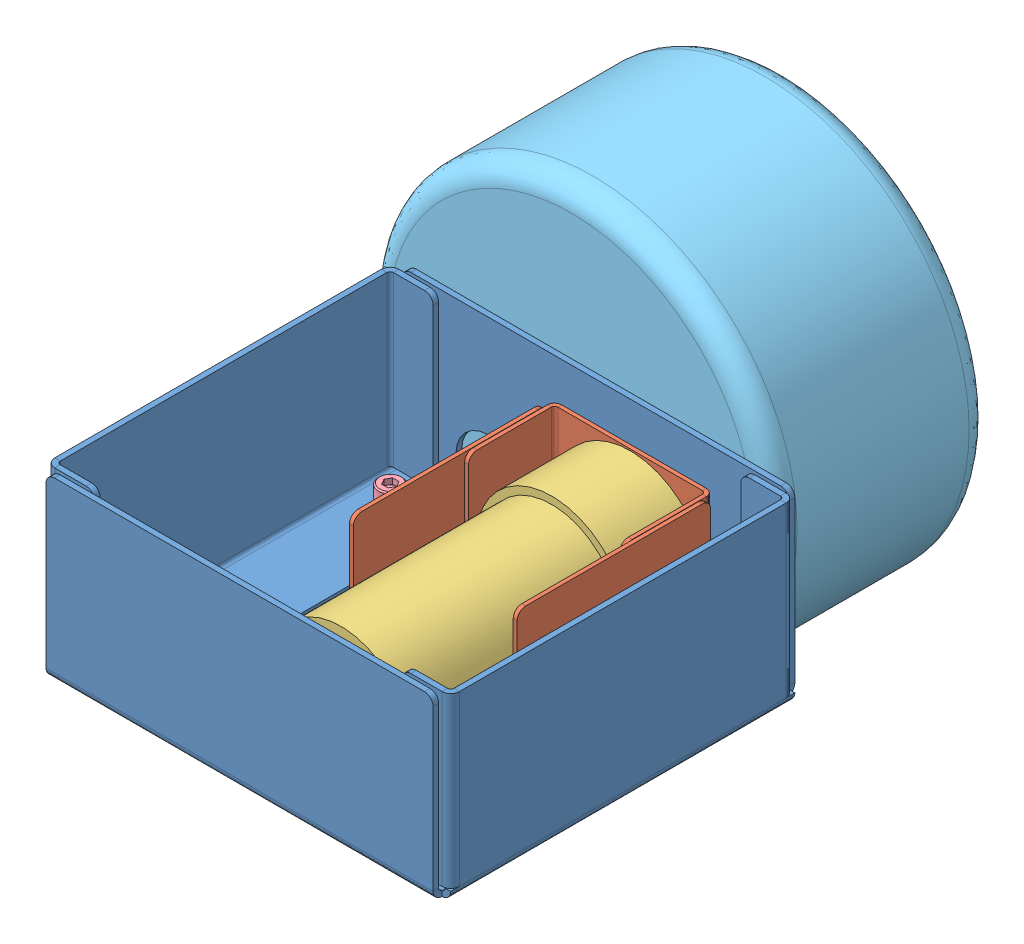
SolidWorks assembly Gear Box Assembly, configuration Default. Lengths in mm.
Overall size (119.55 95 152.1).
8 component instances, 5 part files, 9 mates.
Components (placement in the parent):
- Drive Gear Box-1: Drive Gear Box [Default] at (-52.2615 -43.4792 60.3599) size (94.1 41.29 84.1)
- BarbCole Motor with Fixture-1: BarbCole Motor with Fixture [Default] at (16.6255 -14.6511 26.761) x (0 0 1) z (-1 0 0) size (89.87 36.41 55.14)
  - BarbCole Geared Fixture-1: BarbCole Geared Fixture [Default] at (-41.6291 -27.9181 27.027) size (67.26 36.41 55.14)
  - Motor BarbCole Geared-1: Motor BarbCole Geared [Default] at (-22.4819 -10.3495 9.4562) size (89.87 35.14 35.14)
- socket head cap screw_am-1: socket head cap screw_am [B18.3.1M - 3 x 0.5 x 5 Hex SHCS -- 5NHX] at (-47.2615 -40.4792 53.3599) x (0 -1 0) z (0 0 1) size (8 5.5 5.5)
- socket head cap screw_am-2: socket head cap screw_am [B18.3.1M - 3 x 0.5 x 5 Hex SHCS -- 5NHX] at (-47.2615 -40.4792 -12.6401) x (0 -1 0) z (0 0 1) size (8 5.5 5.5)
- socket head cap screw_am-3: socket head cap screw_am [B18.3.1M - 3 x 0.5 x 5 Hex SHCS -- 5NHX] at (32.7385 -40.4792 20.725) x (0 -1 0) z (0 0 1) size (8 5.5 5.5)
- Tire-1: Tire [Default] at (-32.2615 -34.6792 -89.6921) size (95 95 50)
Mates (geometry in assembly coordinates):
- Coincident1: coincident anti-aligned: plane of Drive Gear Box-1 through (-52.2615 -43.4792 60.3599) normal (0 1 0); plane of BarbCole Motor with Fixture-1/BarbCole Geared Fixture-1 through (-10.4015 -43.4792 -14.8681) normal (0 -1 0)
- Concentric11: concentric aligned: cylinder of Drive Gear Box-1 through (-47.2615 -43.4792 53.3599) axis (0 1 0) radius 1.7; cylinder of socket head cap screw_am-1 through (-47.2615 -8.7292 53.3599) axis (0 1 0) radius 1.5
- Coincident21: coincident anti-aligned: plane of Drive Gear Box-1 through (-52.2615 -43.4792 60.3599) normal (0 1 0); plane of socket head cap screw_am-1 through (-44.5115 -43.4792 53.3599) normal (0 -1 0)
- Concentric21: concentric aligned: cylinder of Drive Gear Box-1 through (-47.2615 -43.4792 -12.6401) axis (0 1 0) radius 1.7; cylinder of socket head cap screw_am-2 through (-47.2615 -8.7292 -12.6401) axis (0 1 0) radius 1.5
- Coincident31: coincident anti-aligned: plane of Drive Gear Box-1 through (-52.2615 -43.4792 60.3599) normal (0 1 0); plane of socket head cap screw_am-2 through (-44.5115 -43.4792 -12.6401) normal (0 -1 0)
- Concentric31: concentric aligned: cylinder of Drive Gear Box-1 through (32.7385 -43.4792 20.725) axis (0 1 0) radius 1.7; cylinder of socket head cap screw_am-3 through (32.7385 -8.7292 20.725) axis (0 1 0) radius 1.5
- Coincident41: coincident anti-aligned: plane of Drive Gear Box-1 through (-52.2615 -43.4792 60.3599) normal (0 1 0); plane of socket head cap screw_am-3 through (35.4885 -43.4792 20.725) normal (0 -1 0)
- Concentric32: concentric anti-aligned: cylinder of Drive Gear Box-1 through (-32.2615 -34.6792 -21.6931) axis (0 0 1) radius 7.5; line of Tire-1 through (-32.2615 -34.6792 -44.6921) axis (0 0 -1)
- Distance1: distance = 18 mm anti-aligned: plane of Tire-1 through (-32.2615 -34.6792 -39.6921) normal (0 0 1); plane of Drive Gear Box-1 through (-52.2615 -43.4792 -21.6921) normal (0 0 -1)
